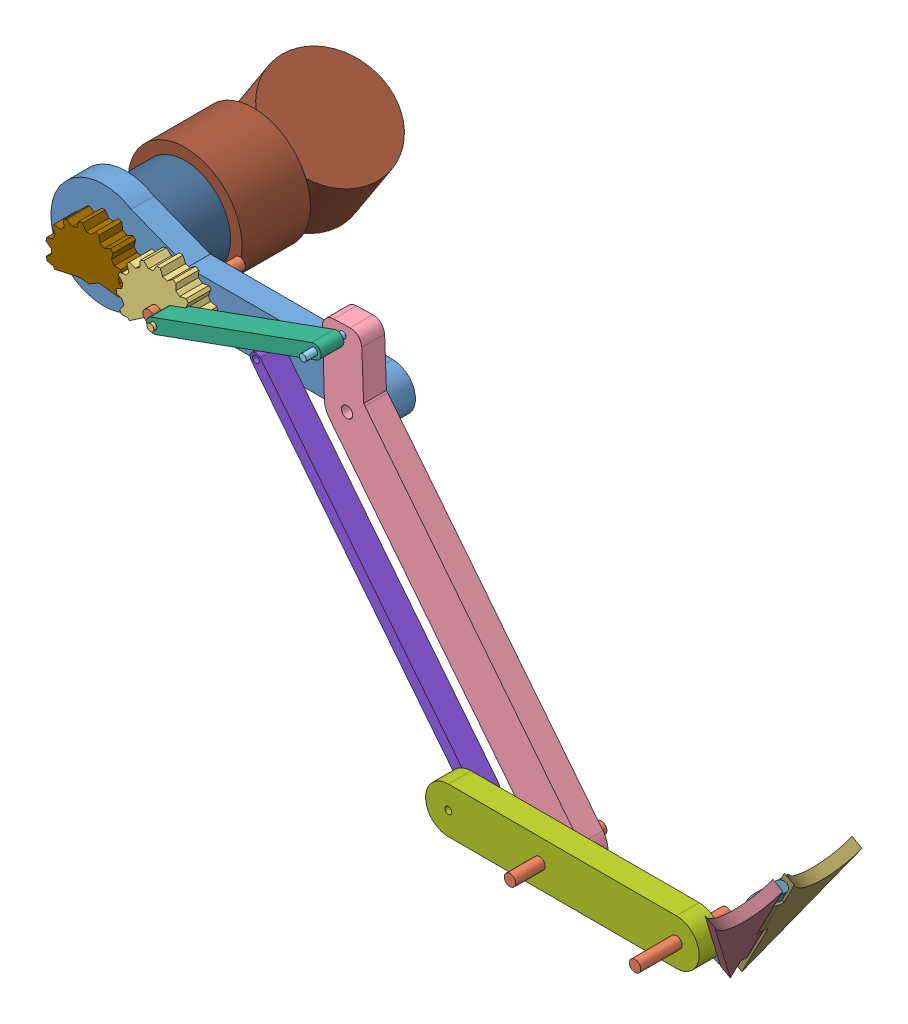
SolidWorks assembly Assemblage_leg_parallele, configuration Défaut. Lengths in mm.
Overall size (339.85 172.54 152.48).
18 component instances, 14 part files, 22 mates.
Components (placement in the parent):
- femur_parallele-1: femur_parallele [Défaut] at (-36.3804 -7.677 100) size (149.91 46.21 10)
- grand axe-1: grand axe [Défaut] at (-36.3804 2.323 87.1079) x (-0.546581 0.837406 0) z (0 0 1) size (5 5 40)
- PIGNON1-2: PIGNON1 [Défaut] at (-36.3804 2.323 113.7636) x (0.998368 -0.057115 0) z (0 0 1) size (34.33 27.43 20)
- tibia_parallele-1: tibia_parallele [Défaut] at (35.7831 -3.889 110) x (0.6212 -0.783652 0) z (0 0 1) size (192.09 33.32 10)
- petit axe-3: petit axe [Défaut] at (41.6437 30.6294 117.4187) x (-0.658639 0.752459 0) z (0 0 1) size (3 3 20)
- segment_L3-1: segment_L3 [Défaut] at (-27.8372 2.232 122.4601) x (0.940053 0.34103 0) z (0 0 1) size (81 6 10)
- grand axe-4: grand axe [Défaut] at (138.0421 -116.792 102.9566) x (0.597942 -0.80154 0) z (0 0 1) size (5 5 40)
- tarto_para-1: tarto_para [Défaut] at (138.0379 -126.792 120) x (1 -0.00041 0) z (0 0 1) size (120 20 10)
- segment_L3 - tibia_parallele-1: segment_L3 - tibia_parallele [Défaut] at (1.6605 0.77 110) x (0.6212 -0.783652 0) z (0 0 1) size (157 5 10)
- grand axe-5: grand axe [Défaut] at (198.042 -116.8167 108.1237) x (0.981676 0.190558 0) z (0 0 1) size (5 5 40)
- PIGNON_moteur-2: PIGNON_moteur [Défaut] at (-67.4715 2.323 123.6642) x (-0.858016 -0.513623 0) z (0 0 -1) size (34.33 27.43 20)
- moteur-1: moteur [Défaut] at (-67.4715 2.323 80) size (40 40 30)
- moteur_hanche-1: moteur_hanche [Défaut] at (-67.4715 2.323 50) x (0.975295 -0.220906 0) z (0 0 1) size (50 50 30)
- moteur_hanche-2: moteur_hanche [Défaut] at (-58.8609 15.4857 25) x (0.83865 -0.544625 0.007054) z (-0.544639 -0.838671 0) size (50 50 30)
- palme_last_v-3: palme_last_v [Défaut] at (272.0977 -126.7907 100.6013) x (-0.093574 0.048447 -0.994433) z (-0.883094 0.457211 0.105372) size (63.26 51.54 27.37)
  - part1_palme-1: part1_palme [Défaut] at (-10.0456 -22.2629 53.5087) x (0.991742 0 -0.128249) z (0.128249 0 0.991742) size (34.09 50 5)
  - part2_palme-1: part2_palme [Défaut] at (-14.3223 -22.2629 59.0993) x (-0.991025 0 0.133679) z (-0.133679 0 -0.991025) size (34.09 50 5)
  - arret_rotation-1: arret_rotation [Défaut] at (-12.1916 -19.7229 56.2981) x (0.105372 0 0.994433) z (0 1 0) size (22.5 18.23 49)
Mates (geometry in assembly coordinates):
- Coaxiale1: concentric aligned: cylinder of femur_parallele-1 through (-36.3804 2.323 110) axis (0 0 -1) radius 2.5; cylinder of grand axe-1 through (-36.3804 2.323 127.1079) axis (0 0 -1) radius 2.5
- Coaxiale6: concentric anti-aligned: cylinder of grand axe-1 through (-36.3804 2.323 127.1079) axis (0 0 -1) radius 2.5; cylinder of PIGNON1-2 through (-36.3804 2.323 113.7636) axis (0 0 1) radius 2.5
- Coaxiale11: concentric aligned: cylinder of PIGNON1-2 through (-28.8603 5.0521 133.7636) axis (0 0 -1) radius 1.5; cylinder of segment_L3-1 through (-28.8603 5.0521 132.4601) axis (0 0 -1) radius 1.5
- Coaxiale12: concentric aligned: cylinder of petit axe-3 through (41.6437 30.6294 137.4187) axis (0 0 -1) radius 1.5; cylinder of segment_L3-1 through (41.6437 30.6294 132.4601) axis (0 0 -1) radius 1.5
- Coaxiale15: concentric aligned: cylinder of grand axe-4 through (138.0421 -116.792 142.9566) axis (0 0 -1) radius 2.5; cylinder of tarto_para-1 through (138.0421 -116.792 130) axis (0 0 -1) radius 2.5
- Coaxiale20: concentric aligned: cylinder of tarto_para-1 through (198.042 -116.8167 130) axis (0 0 -1) radius 2.5; cylinder of grand axe-5 through (198.042 -116.8167 148.1237) axis (0 0 -1) radius 2.5
- Coaxiale24: concentric anti-aligned: cylinder of femur_parallele-1 through (-67.4715 2.323 110) axis (0 0 -1) radius 2.5; cylinder of PIGNON_moteur-2 through (-67.4715 2.323 103.6642) axis (0 0 1) radius 2.5
- Coaxiale26: concentric aligned: cylinder of tibia_parallele-1 through (138.0421 -116.792 120) axis (0 0 -1) radius 2.5; cylinder of grand axe-4 through (138.0421 -116.792 142.9566) axis (0 0 -1) radius 2.5
- Coaxiale27: concentric aligned: cylinder of tibia_parallele-1 through (41.6437 30.6294 120) axis (0 0 -1) radius 1.5; cylinder of petit axe-3 through (41.6437 30.6294 137.4187) axis (0 0 -1) radius 1.5
- Coaxiale29: concentric aligned: cylinder of femur_parallele-1 through (-67.4715 2.323 110) axis (0 0 -1) radius 2.5; cylinder of moteur-1 through (-67.4715 2.323 110) axis (0 0 -1) radius 2.5
- Coïncidente1: coincident anti-aligned: plane of femur_parallele-1 through (-73.1882 2.323 100) normal (0 0 -1); plane of moteur-1 through (-67.4715 2.323 100) normal (0 0 1)
- Coaxiale32: concentric aligned: cylinder of moteur-1 through (-67.4715 2.323 100) axis (0 0 -1) radius 20; cylinder of moteur_hanche-1 through (-67.4715 2.323 80) axis (0 0 -1) radius 25
- Coïncidente3: coincident anti-aligned: plane of moteur-1 through (-67.4715 2.323 80) normal (0 0 -1); plane of moteur_hanche-1 through (-67.4715 2.323 80) normal (0 0 1)
- Tangent1: tangent anti-aligned: plane of moteur_hanche-1 through (-67.4715 2.323 50) normal (0 0 -1); cylinder of moteur_hanche-2 through (-75.2001 -9.6744 25) axis (0.544639 0.838671 0) radius 25
- Coaxiale35: concentric aligned: cylinder of femur_parallele-1 through (3.6196 2.323 110) axis (0 0 -1) radius 1.5; cylinder of segment_L3 - tibia_parallele-1 through (3.6196 2.323 120) axis (0 0 -1) radius 1.5
- Coaxiale37: concentric aligned: cylinder of tarto_para-1 through (98.042 -116.7921 130) axis (0 0 -1) radius 1.5; cylinder of segment_L3 - tibia_parallele-1 through (98.042 -116.7921 120) axis (0 0 -1) radius 1.5
- Coïncidente5: coincident anti-aligned: plane of femur_parallele-1 through (-73.1882 2.323 110) normal (0 0 1); plane of tibia_parallele-1 through (43.6196 2.323 110) normal (0 0 -1)
- Coïncidente6: coincident anti-aligned: plane of tibia_parallele-1 through (43.6196 2.323 120) normal (0 0 1); plane of tarto_para-1 through (198.042 -116.8167 120) normal (0 0 -1)
- Coïncidente7: coincident anti-aligned: plane of tarto_para-1 through (198.042 -116.8167 120) normal (0 0 -1); plane of segment_L3 - tibia_parallele-1 through (3.6196 2.323 120) normal (0 0 1)
- Coïncidente8: coincident aligned: cylinder of grand axe-5 through (198.042 -116.8167 148.1237) axis (0 0 -1) radius 2.5; circle of palme_last_v-3/arret_rotation-1
- Coïncidente9: coincident anti-aligned: plane of tarto_para-1 through (198.042 -116.8167 120) normal (0 0 -1); plane of palme_last_v-3/arret_rotation-1 through (210.0613 -127.6404 120) normal (0 0 1)
- Coaxiale38: concentric anti-aligned: circle of femur_parallele-1; cylinder of tibia_parallele-1 through (43.6196 2.323 120) axis (0 0 -1) radius 2.5
